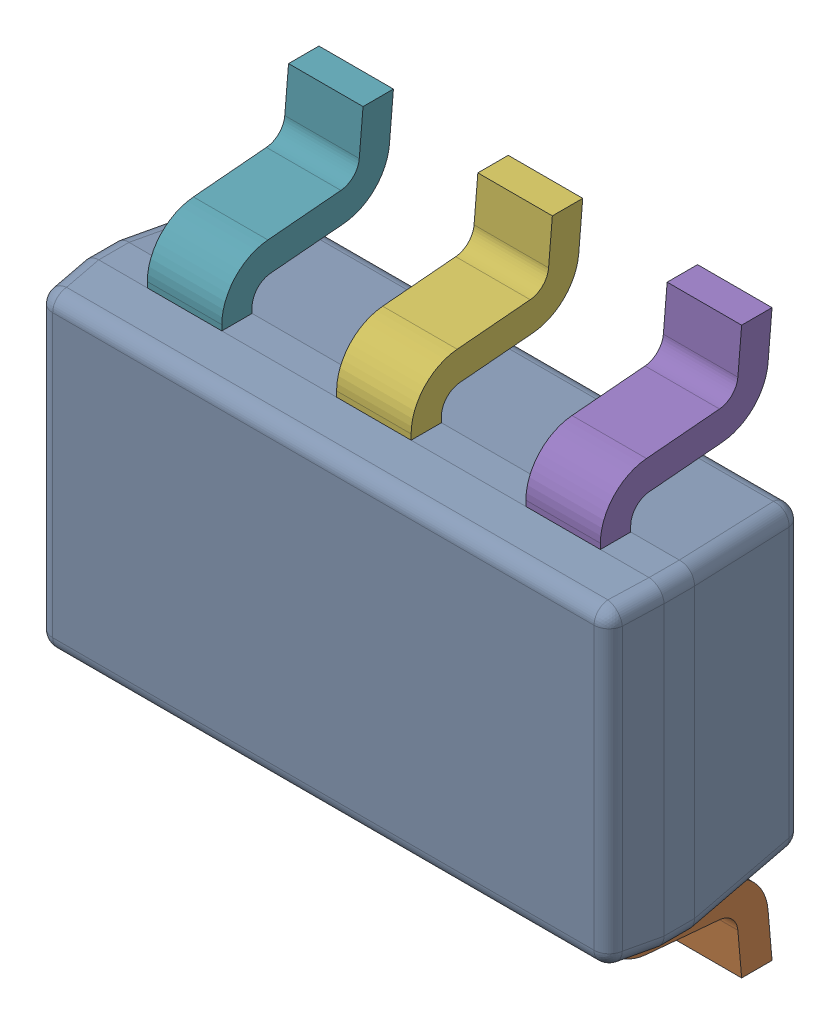
SolidWorks assembly U2.step, configuration Default. Lengths in mm.
Overall size (2.93 2.84 1.12).
8 component instances, 2 part files, 0 mates.
Components (placement in the parent):
- sot-23-6.step-1: sot-23-6.step [Default] at (58.5469 61.2141 0.87) x (1 0 0) z (0 -1 0) size (2.93 1.12 2.84)
  - BODY_MF06A.step-1: BODY_MF06A.step [Default] at origin size (2.93 1.02 1.61)
  - LEAD_MF06A.step-1: LEAD_MF06A.step [Default] at (0.9525 -0.6604 0.9652) size (0.37 0.86 0.62)
  - LEAD_MF06A.step-2: LEAD_MF06A.step [Default] at (0 -0.6604 0.9652) size (0.37 0.86 0.62)
  - LEAD_MF06A.step-3: LEAD_MF06A.step [Default] at (-0.9525 -0.6604 0.9652) size (0.37 0.86 0.62)
  - LEAD_MF06A.step-4: LEAD_MF06A.step [Default] at (0.9525 -0.6604 -0.9652) x (-1 0 0) z (0 0 -1) size (0.37 0.86 0.62)
  - LEAD_MF06A.step-5: LEAD_MF06A.step [Default] at (0 -0.6604 -0.9652) x (-1 0 0) z (0 0 -1) size (0.37 0.86 0.62)
  - LEAD_MF06A.step-6: LEAD_MF06A.step [Default] at (-0.9525 -0.6604 -0.9652) x (-1 0 0) z (0 0 -1) size (0.37 0.86 0.62)
